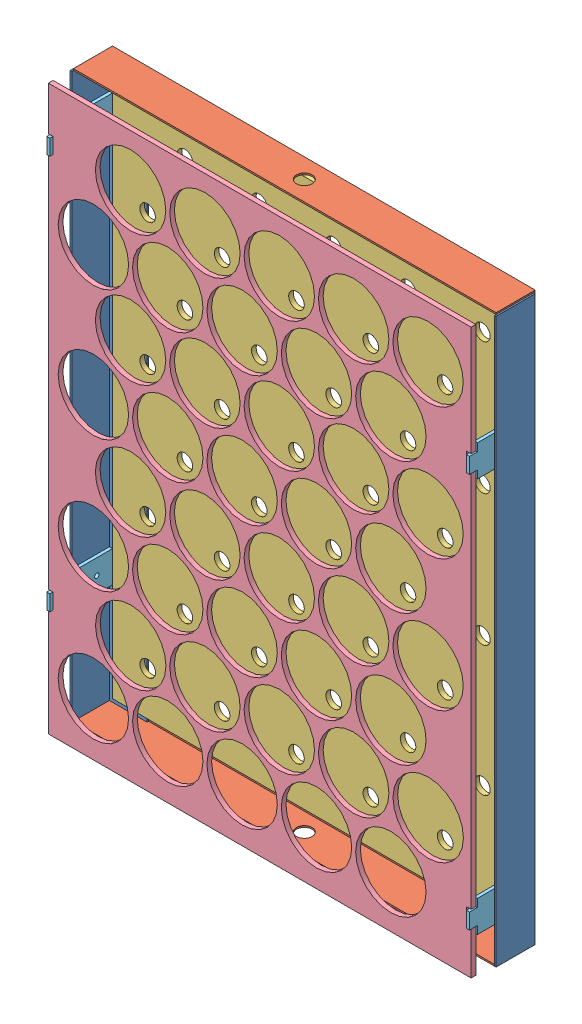
SolidWorks assembly Bandeja_Huevos_27x36x2.5, configuration Predeterminado. Lengths in mm.
Overall size (272 362 42).
10 component instances, 5 part files, 24 mates.
Components (placement in the parent):
- Soporte_Bandeja_Horizonta_40x2.5x0.1-1: Soporte_Bandeja_Horizonta_40x2.5x0.1 [Predeterminado] at (53.9361 154.3977 387.5) size (25 360 25)
- Soporte_Bandeja_Horizonta_40x2.5x0.1-4: Soporte_Bandeja_Horizonta_40x2.5x0.1 [Predeterminado] at (-274.8673 -152.6319 387.5) x (-1 0 0) z (0 0 1) size (25 360 25)
- Soporte_Bandeja_Vertical_27x2.5x0.1-2: Soporte_Bandeja_Vertical_27x2.5x0.1 [Predeterminado] at (-218.9804 210.2846 386.5) x (0 1 0) z (0 0 1) size (25 270 25)
- Soporte_Bandeja_Vertical_27x2.5x0.1-3: Soporte_Bandeja_Vertical_27x2.5x0.1 [Predeterminado] at (-1.9508 -208.5189 386.5) x (0 -1 0) z (0 0 1) size (25 270 25)
- Bandeja_Down_27x36x0.5-1: Bandeja_Down_27x36x0.5 [Predeterminado] at (-199.9841 -101.0844 388.5) x (0 1 0) z (0 0 1) size (350 260 3)
- Bandeja_Up_27x36x0.3-1: Bandeja_Up_27x36x0.3 [Predeterminado] at (-21.9173 102.8502 423.5) x (0 -1 0) z (0 0 1) size (360 270.04 3)
- Bandeja_Huevo_levantador-1: Bandeja_Huevo_levantador [Predeterminado] at (-245.4656 -92.1249 405.9419) x (0 1 0) z (1 0 0) size (20 40 2)
- Bandeja_Huevo_levantador-2: Bandeja_Huevo_levantador [Predeterminado] at (24.5344 -158.1093 405.9419) x (0 -1 0) z (-1 0 0) size (20 40 2)
- Bandeja_Huevo_levantador-3: Bandeja_Huevo_levantador [Predeterminado] at (24.5344 93.8907 405.9419) x (0 -1 0) z (-1 0 0) size (20 40 2)
- Bandeja_Huevo_levantador-4: Bandeja_Huevo_levantador [Predeterminado] at (-243.4656 135.8907 405.9419) x (0 -1 0) z (-1 0 0) size (20 40 2)
Mates (geometry in assembly coordinates):
- Coincidente1: coincident aligned: line of Soporte_Bandeja_Horizonta_40x2.5x0.1-1 through (24.5344 180.8829 412.5) axis (0 0 -1); line of Soporte_Bandeja_Vertical_27x2.5x0.1-2 through (24.5344 180.8829 411.5) axis (0 0 -1)
- Coincidente2: coincident aligned: circle of Soporte_Bandeja_Horizonta_40x2.5x0.1-1; circle of Soporte_Bandeja_Vertical_27x2.5x0.1-2
- Coincidente3: coincident aligned: line of Soporte_Bandeja_Horizonta_40x2.5x0.1-1 through (24.5344 -179.1171 412.5) axis (0 0 -1); line of Soporte_Bandeja_Vertical_27x2.5x0.1-3 through (24.5344 -179.1171 411.5) axis (0 0 -1)
- Coincidente4: coincident aligned: circle of Soporte_Bandeja_Horizonta_40x2.5x0.1-1; circle of Soporte_Bandeja_Vertical_27x2.5x0.1-3
- Coincidente5: coincident aligned: line of Soporte_Bandeja_Horizonta_40x2.5x0.1-4 through (-245.4656 180.8829 412.5) axis (0 0 -1); line of Soporte_Bandeja_Vertical_27x2.5x0.1-2 through (-245.4656 180.8829 411.5) axis (0 0 -1)
- Coincidente7: coincident aligned: circle of Soporte_Bandeja_Horizonta_40x2.5x0.1-4; circle of Soporte_Bandeja_Vertical_27x2.5x0.1-2
- Coincidente9: coincident anti-aligned: plane of Soporte_Bandeja_Horizonta_40x2.5x0.1-4 through (-274.8673 -152.6319 388.5) normal (0 0 1); plane of Bandeja_Down_27x36x0.5-1 through (-199.9841 -101.0844 388.5) normal (0 0 -1)
- Coincidente10: coincident aligned: circle of Soporte_Bandeja_Horizonta_40x2.5x0.1-4; circle of Bandeja_Down_27x36x0.5-1
- Coincidente11: coincident aligned: circle of Soporte_Bandeja_Horizonta_40x2.5x0.1-1; circle of Bandeja_Down_27x36x0.5-1
- Coincidente17: coincident anti-aligned: plane of Soporte_Bandeja_Vertical_27x2.5x0.1-2 through (-245.4656 180.8829 411.5) normal (0 -1 0); plane of Bandeja_Up_27x36x0.3-1 through (23.5642 180.8829 426.5) normal (0 1 0)
- Coincidente18: coincident anti-aligned: plane of Soporte_Bandeja_Horizonta_40x2.5x0.1-4 through (-245.4656 -179.1171 412.5) normal (1 0 0); plane of Bandeja_Huevo_levantador-1 through (-245.4656 -92.1249 405.9419) normal (-1 0 0)
- Coincidente19: coincident anti-aligned: plane of Soporte_Bandeja_Horizonta_40x2.5x0.1-4 through (-274.8673 -152.6319 388.5) normal (0 0 1); plane of Bandeja_Huevo_levantador-1 through (-243.4656 -114.1171 388.5) normal (0 0 -1)
- Coincidente20: coincident anti-aligned: plane of Bandeja_Up_27x36x0.3-1 through (-21.9173 102.8502 423.5) normal (0 0 -1); plane of Bandeja_Huevo_levantador-1 through (-243.4656 -109.1171 423.5) normal (0 0 1)
- Coincidente21: coincident anti-aligned: plane of Bandeja_Up_27x36x0.3-1 through (-243.4656 -99.1171 426.5) normal (-1 0 0); plane of Bandeja_Huevo_levantador-1 through (-243.4656 -92.1249 405.9419) normal (1 0 0)
- Coincidente22: coincident anti-aligned: plane of Bandeja_Up_27x36x0.3-1 through (-243.4656 -99.1171 426.5) normal (0 -1 0); plane of Bandeja_Huevo_levantador-1 through (-243.4656 -99.1171 428.5) normal (0 1 0)
- Coincidente23: coincident anti-aligned: plane of Soporte_Bandeja_Horizonta_40x2.5x0.1-1 through (53.9361 154.3977 388.5) normal (0 0 1); plane of Bandeja_Huevo_levantador-2 through (22.5344 -136.1171 388.5) normal (0 0 -1)
- Coincidente24: coincident anti-aligned: plane of Soporte_Bandeja_Horizonta_40x2.5x0.1-1 through (53.9361 154.3977 388.5) normal (0 0 1); plane of Bandeja_Huevo_levantador-3 through (22.5344 115.8829 388.5) normal (0 0 -1)
- Coincidente25: coincident anti-aligned: plane of Soporte_Bandeja_Horizonta_40x2.5x0.1-4 through (-274.8673 -152.6319 388.5) normal (0 0 1); plane of Bandeja_Huevo_levantador-4 through (-245.4656 157.8829 388.5) normal (0 0 -1)
- Coincidente26: coincident anti-aligned: plane of Soporte_Bandeja_Horizonta_40x2.5x0.1-1 through (24.5344 180.8829 412.5) normal (-1 0 0); plane of Bandeja_Huevo_levantador-2 through (24.5344 -158.1093 405.9419) normal (1 0 0)
- Coincidente27: coincident anti-aligned: plane of Soporte_Bandeja_Horizonta_40x2.5x0.1-1 through (24.5344 180.8829 412.5) normal (-1 0 0); plane of Bandeja_Huevo_levantador-3 through (24.5344 93.8907 405.9419) normal (1 0 0)
- Coincidente28: coincident anti-aligned: plane of Soporte_Bandeja_Horizonta_40x2.5x0.1-4 through (-245.4656 -179.1171 412.5) normal (1 0 0); plane of Bandeja_Huevo_levantador-4 through (-245.4656 135.8907 405.9419) normal (-1 0 0)
- Coincidente29: coincident anti-aligned: plane of Bandeja_Up_27x36x0.3-1 through (-243.4358 152.8829 426.5) normal (0 -1 0); plane of Bandeja_Huevo_levantador-4 through (-245.4656 152.8829 428.5) normal (0 1 0)
- Coincidente30: coincident anti-aligned: plane of Bandeja_Up_27x36x0.3-1 through (23.5633 -151.1171 426.5) normal (0 1 0); plane of Bandeja_Huevo_levantador-2 through (22.5344 -151.1171 428.5) normal (0 -1 0)
- Coincidente31: coincident anti-aligned: plane of Bandeja_Up_27x36x0.3-1 through (23.5642 100.8829 426.5) normal (0 1 0); plane of Bandeja_Huevo_levantador-3 through (22.5344 100.8829 428.5) normal (0 -1 0)
